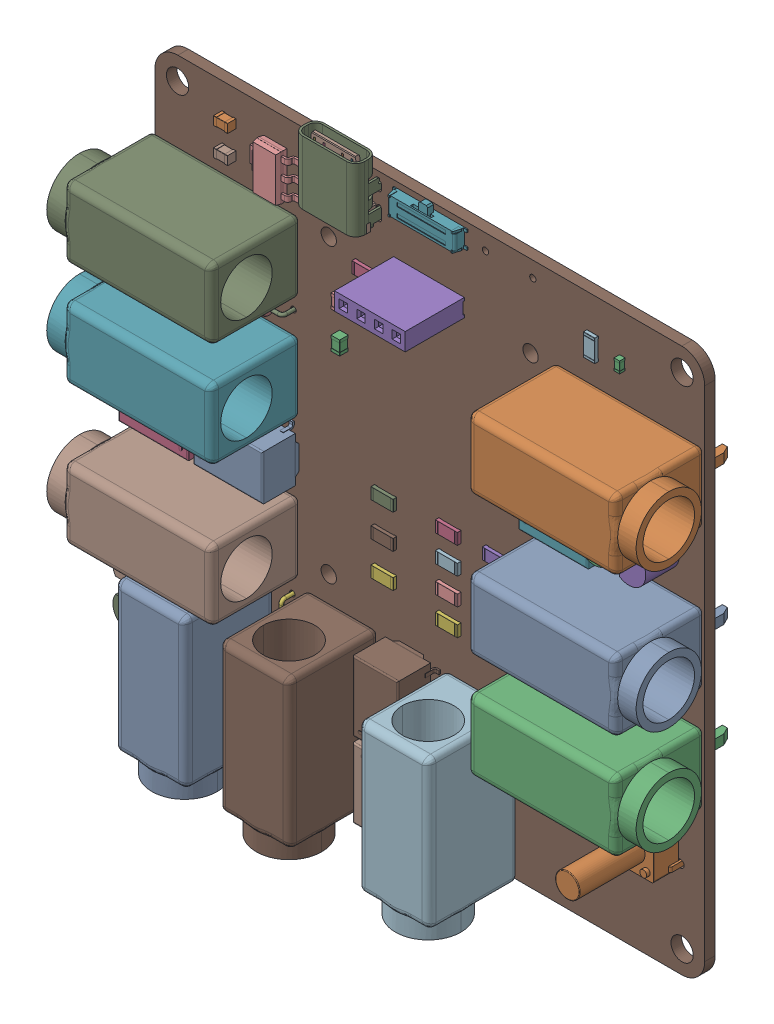
SolidWorks assembly Logic testing, configuration Default. Lengths in mm.
Overall size (84.69 83.26 18.9).
47 component instances, 13 part files, 0 mates.
Components (placement in the parent):
- Logic testing(2)-1: Logic testing(2) [Default] at origin size (84.69 83.26 18.9)
  - Relay_DPDT_Omron_G6K-2F-1: Relay_DPDT_Omron_G6K-2F [Default] at (-23.44 -1.875 1.595) x (0 1 0) z (0 0 1) size (7.8 10 5.58)
  - SW_PUSH_6mm_H13mm-1: SW_PUSH_6mm_H13mm [Default] at (36 -25.375 1.595) x (-1 0 0) z (0 0 1) size (7.17 6 16.5)
  - C_0603_1608Metric-1: C_0603_1608Metric [Default] at (27.75 32.875 1.595) x (0 1 0) z (0 0 1) size (1.6 0.8 0.8)
  - R_1206_3216Metric-1: R_1206_3216Metric [Default] at (-9 25.875 1.595) size (3.2 1.6 0.55)
  - PinSocket_1x04_P2.54mm_Vertical-1: PinSocket_1x04_P2.54mm_Vertical [Default] at (3.775 28.375 1.595) x (0 -1 0) z (0 0 1) size (2.54 10.16 11.6)
  - R_1206_3216Metric-2: R_1206_3216Metric [Default] at (9.75 -4.2083 1.595) size (3.2 1.6 0.55)
  - 4mm PCB Mount-1: 4mm PCB Mount [Default] at (-29.04 8.125 8.095) x (0 1 0) z (1 0 0) size (10.21 18.8 24)
  - 4mm PCB Mount-2: 4mm PCB Mount [Default] at (-29.04 -11.875 8.095) x (0 1 0) z (1 0 0) size (10.21 18.8 24)
  - 4mm PCB Mount-3: 4mm PCB Mount [Default] at (-29.04 23.125 8.095) x (0 1 0) z (1 0 0) size (10.21 18.8 24)
  - SOT-223-1: SOT-223 [Default] at (-22 32.375 1.595) x (-1 0 0) z (0 0 1) size (7 6.5 1.7)
  - R_1206_3216Metric-3: R_1206_3216Metric [Default] at (-6.25 -5.75 1.595) x (-1 0 0) z (0 0 1) size (3.2 1.6 0.55)
  - R_1206_3216Metric-4: R_1206_3216Metric [Default] at (23.5 32.875 1.595) x (0 1 0) z (0 0 1) size (3.2 1.6 0.55)
  - 4mm PCB Mount-4: 4mm PCB Mount [Default] at (29 3.375 8.095) x (0 -1 0) z (-1 0 0) size (10.21 18.8 24)
  - 4mm PCB Mount-5: 4mm PCB Mount [Default] at (29 23.375 8.095) x (0 -1 0) z (-1 0 0) size (10.21 18.8 24)
  - 4mm PCB Mount-6: 4mm PCB Mount [Default] at (29 -11.625 8.095) x (0 -1 0) z (-1 0 0) size (10.21 18.8 24)
  - R_1206_3216Metric-5: R_1206_3216Metric [Default] at (9.75 -8.0417 1.595) size (3.2 1.6 0.55)
  - TO-92_Inline-1: TO-92_Inline [Default] at (36 16.625 1.595) x (0 -1 0) z (0 0 1) size (4.83 3.75 9.8)
  - R_1206_3216Metric-6: R_1206_3216Metric [Default] at (3 -11.875 1.595) size (3.2 1.6 0.55)
  - SW_SP3T_PCM13-1: SW_SP3T_PCM13 [Default] at (0.25 36.745 1.595) x (-1 0 0) z (0 0 1) size (10.65 4.65 2)
  - TO-92_Inline-2: TO-92_Inline [Default] at (-37.02 -21.485 1.595) size (4.83 3.75 9.8)
  - USB_C_Receptacle_GCT_USB4085-1: USB_C_Receptacle_GCT_USB4085 [Default] at (-8.625 32.95 1.595) x (-1 0 0) z (0 0 1) size (8.94 9.17 5.56)
  - Relay_DPDT_Omron_G6K-2F-2: Relay_DPDT_Omron_G6K-2F [Default] at (23.25 13.375 1.595) x (0 1 0) z (0 0 1) size (7.8 10 5.58)
  - Relay_DPDT_Omron_G6K-2F-3: Relay_DPDT_Omron_G6K-2F [Default] at (-2.25 -33.275 1.595) size (7.8 10 5.58)
  - D_DO-35_SOD27_P7.62mm_Horizontal-1: D_DO-35_SOD27_P7.62mm_Horizontal [Default] at (-27.21 15.775 1.595) size (8.12 2.02 5.01)
  - Relay_DPDT_Omron_G6K-2F-4: Relay_DPDT_Omron_G6K-2F [Default] at (-2.25 -22.465 1.595) x (-1 0 0) z (0 0 1) size (7.8 10 5.58)
  - R_1206_3216Metric-7: R_1206_3216Metric [Default] at (3 -4.2083 1.595) x (-1 0 0) z (0 0 1) size (3.2 1.6 0.55)
  - D_DO-35_SOD27_P7.62mm_Horizontal-2: D_DO-35_SOD27_P7.62mm_Horizontal [Default] at (-19.75 -29.775 1.595) x (0 -1 0) z (0 0 1) size (8.12 2.02 5.01)
  - TO-92_Inline-3: TO-92_Inline [Default] at (31 16.645 1.595) x (0 -1 0) z (0 0 1) size (4.83 3.75 9.8)
  - Relay_DPDT_Omron_G6K-2F-5: Relay_DPDT_Omron_G6K-2F [Default] at (-34.19 -1.875 1.595) x (0 -1 0) z (0 0 1) size (7.8 10 5.58)
  - R_1206_3216Metric-8: R_1206_3216Metric [Default] at (9.75 -0.375 1.595) size (3.2 1.6 0.55)
  - R_1206_3216Metric-9: R_1206_3216Metric [Default] at (-6.25 -10.625 1.595) x (-1 0 0) z (0 0 1) size (3.2 1.6 0.55)
  - D_DO-35_SOD27_P7.62mm_Horizontal-3: D_DO-35_SOD27_P7.62mm_Horizontal [Default] at (-29.46 15.775 1.595) x (-1 0 0) z (0 0 1) size (8.12 2.02 5.01)
  - R_1206_3216Metric-10: R_1206_3216Metric [Default] at (-6.25 -0.875 1.595) x (-1 0 0) z (0 0 1) size (3.2 1.6 0.55)
  - R_1206_3216Metric-11: R_1206_3216Metric [Default] at (3 -8.0417 1.595) size (3.2 1.6 0.55)
  - 4mm PCB Mount-7: 4mm PCB Mount [Default] at (-12.25 -28.375 8.095) x (-1 0 0) z (0 1 0) size (10.21 18.8 24)
  - 4mm PCB Mount-8: 4mm PCB Mount [Default] at (7.75 -28.375 8.095) x (-1 0 0) z (0 1 0) size (10.21 18.8 24)
  - 4mm PCB Mount-9: 4mm PCB Mount [Default] at (-27.25 -28.375 8.095) x (-1 0 0) z (0 1 0) size (10.21 18.8 24)
  - C_0805_2012Metric-1: C_0805_2012Metric [Default] at (-28.75 34.875 1.595) x (-1 0 0) z (0 0 1) size (2 1.25 1.25)
  - C_0805_2012Metric-2: C_0805_2012Metric [Default] at (-12.25 15.625 1.595) x (0 1 0) z (0 0 1) size (2 1.25 1.25)
  - R_1206_3216Metric-12: R_1206_3216Metric [Default] at (3 -0.375 1.595) x (-1 0 0) z (0 0 1) size (3.2 1.6 0.55)
  - R_1206_3216Metric-13: R_1206_3216Metric [Default] at (9.75 -11.875 1.595) size (3.2 1.6 0.55)
  - D_DO-35_SOD27_P7.62mm_Horizontal-4: D_DO-35_SOD27_P7.62mm_Horizontal [Default] at (-19.75 -27.275 1.595) x (0 1 0) z (0 0 1) size (8.12 2.02 5.01)
  - C_0805_2012Metric-3: C_0805_2012Metric [Default] at (-28.75 30.875 1.595) x (-1 0 0) z (0 0 1) size (2 1.25 1.25)
  - TO-92_Inline-4: TO-92_Inline [Default] at (-34.48 -26.375 1.595) x (-1 0 0) z (0 0 1) size (4.83 3.75 9.8)
  - C_0805_2012Metric-4: C_0805_2012Metric [Default] at (-12.25 20.875 1.595) x (0 -1 0) z (0 0 1) size (2 1.25 1.25)
  - Logic testing_PCB-1: Logic testing_PCB [Default] at origin size (79 78.25 1.51)
